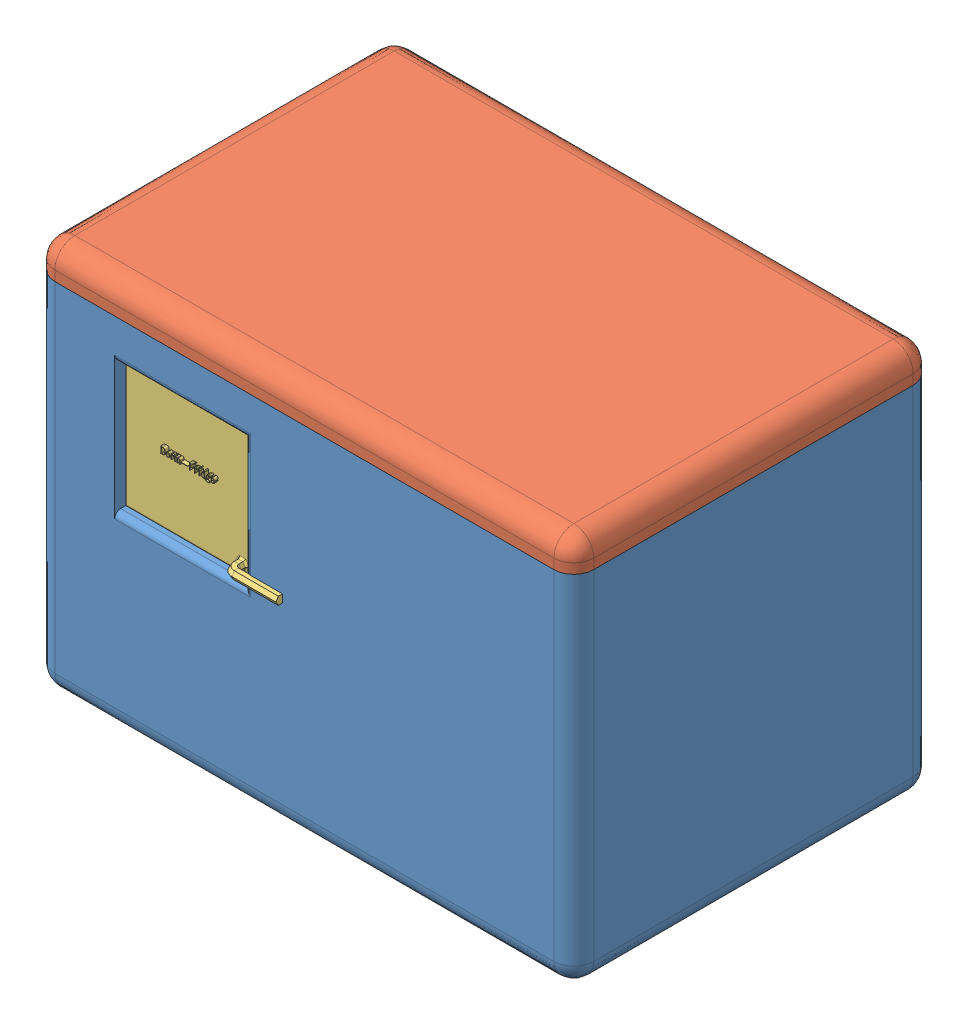
SolidWorks assembly fridge, configuration 默认. Lengths in mm.
Overall size (270 195 183.2).
4 component instances, 4 part files, 6 mates.
Components (placement in the parent):
- box-body-1: box-body [默认] at (1.9915 -134.8087 270) size (270 180 180)
- box-cover-1: box-cover [默认] at (1.9915 40.1913 270) size (270 20 180)
- semiconductor-1: semiconductor [默认] at (-60.5085 -7.3087 350) size (84 65 13.2)
- copper-radiator-1: copper-radiator [默认] at (-60.5085 -7.3087 349) x (1 0 0) z (0 1 0) size (65 31 65)
Mates (geometry in assembly coordinates):
- Coincident1: coincident anti-aligned: line of box-body-1 through (-123.0085 45.1913 360) axis (1 0 0); line of box-cover-1 through (126.9915 45.1913 360) axis (-1 0 0)
- Coincident2: coincident: point of box-body-1; point of box-cover-1
- Coincident3: coincident: point of box-body-1; point of semiconductor-1
- Coincident4: coincident anti-aligned: plane of semiconductor-1 through (-60.5085 -7.3087 350) normal (0 0 -1); plane of copper-radiator-1 through (-51.6122 -7.3087 350) normal (0 0 1)
- Coincident6: coincident anti-aligned: plane of box-body-1 through (-93.0085 -39.8087 340) normal (0 1 0); plane of copper-radiator-1 through (-93.0085 -39.8087 319) normal (0 -1 0)
- Coincident7: coincident anti-aligned: plane of box-body-1 through (-93.0085 25.1913 340) normal (1 0 0); plane of copper-radiator-1 through (-93.0085 25.1913 319) normal (-1 0 0)
